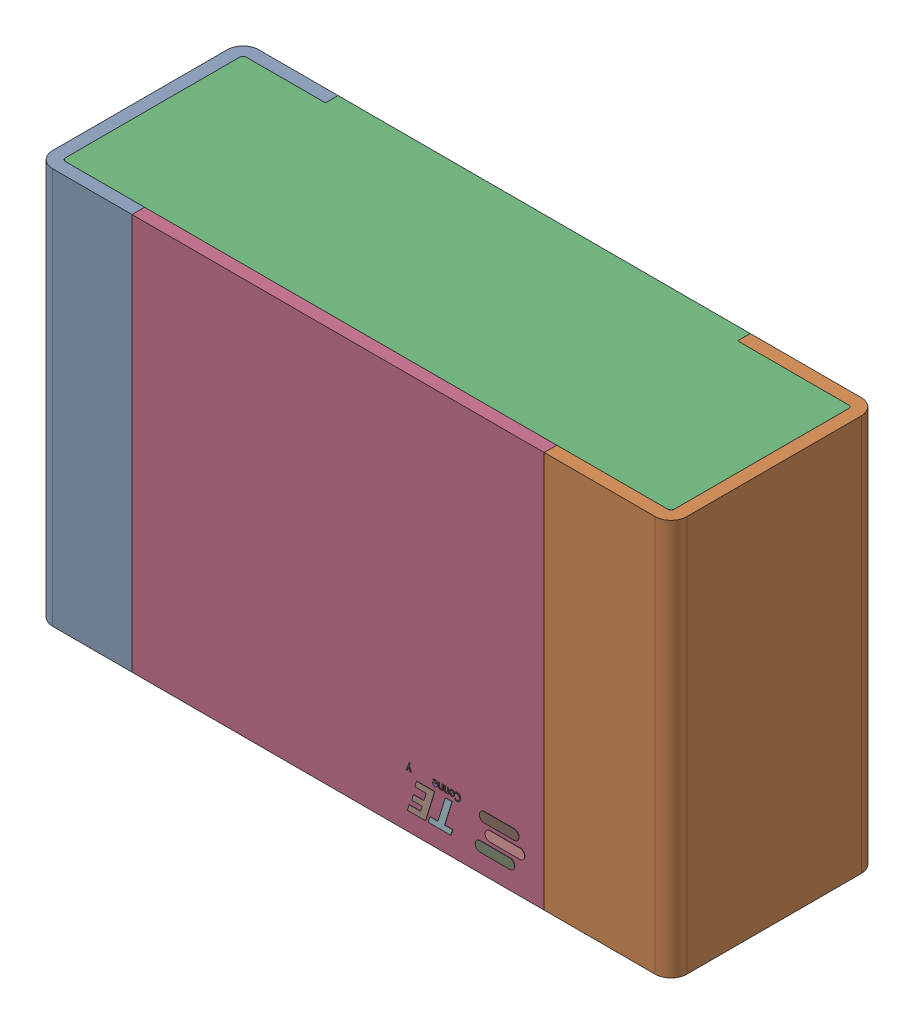
SolidWorks assembly R14.step, configuration Default. Lengths in mm.
Overall size (2 1.25 0.65).
5 component instances, 4 part files, 0 mates.
Components (placement in the parent):
- Res_TE_Connectivity_CPF0805B66R5E1_eec.step-1: Res_TE_Connectivity_CPF0805B66R5E1_eec.step [Default] at (37.973 58.828 0) x (-1 0 0) z (0 0 1) size (2 1.25 0.65)
  - 1.step-1: 1.step [Default] at origin size (2 1.25 0.65)
  - 2.step-1: 2.step [Default] at origin size (1.92 1.25 0.61)
  - 3.step-1: 3.step [Default] at origin size (1.3 1.25 0.04)
  - TE connectivity Logo 1 (2).step-1: TE connectivity Logo 1 (2).step [Default] at (5.4285 0.313 0.551) x (-1 0 0) z (0 0 1) size (0.37 0.13 0.11)
